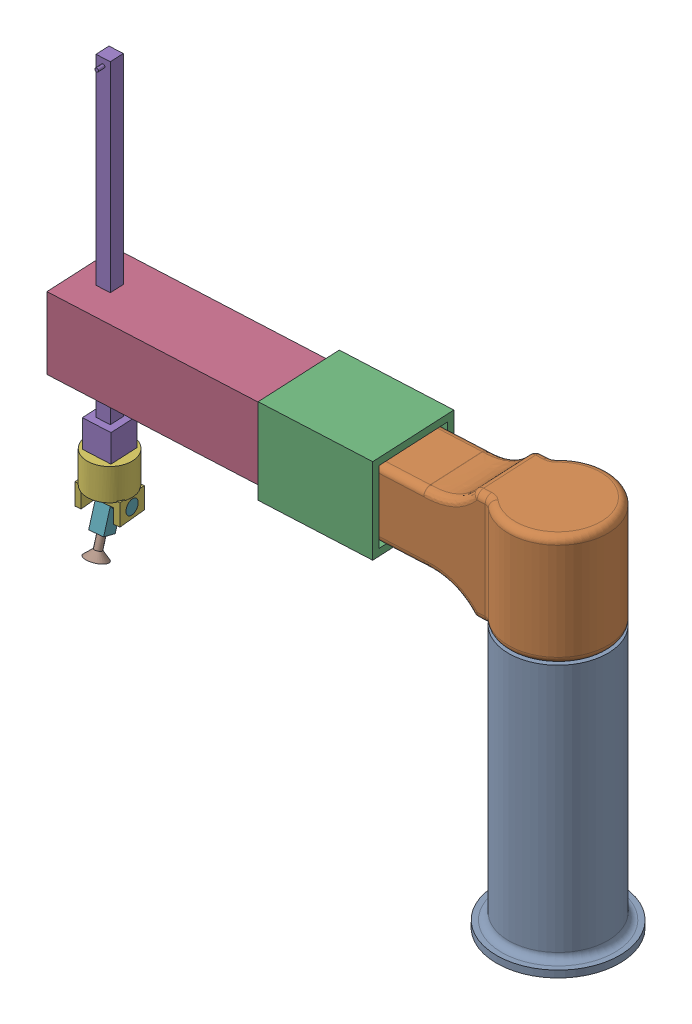
SolidWorks assembly Full_Assem_2023, configuration Default. Lengths in mm.
Overall size (758.51 810.22 185.22).
7 component instances, 7 part files, 12 mates.
Components (placement in the parent):
- JayRPPBase-1: JayRPPBase [Default] at (685.9932 606.079 1289.2915) size (180 424 180)
- JayRPPRotation-1: JayRPPRotation [Default] at (685.9932 990.079 1289.2915) x (-0.998787 0 0.04923) z (-0.04923 0 -0.998787) size (464.5 166.03 145)
- JayRPPPrismatic1-2: JayRPPPrismatic1 [Default] at (324.1942 1071.079 1307.1244) x (-0.998787 0 0.04923) z (0.04923 0 0.998787) size (464 125 125)
- JayRPPPrismatic2-1: JayRPPPrismatic2 [Default] at (60.5143 916.3025 1320.1209) x (0.998787 0 -0.04923) z (0.04923 0 0.998787) size (40 540 40)
- jaywrist1-1: jaywrist1 [Default] at (60.5143 870.3025 1320.1209) x (-0.101882 0 -0.994796) z (0.994796 0 -0.101882) size (65 75.53 65)
- jaywrist2-1: jaywrist2 [Default] at (60.5143 855.5395 1320.1209) x (0.096679 0.315479 0.943995) z (0.994796 0 -0.101882) size (20 50 60)
- Jaytool-1: Jaytool [Default] at (62.7643 789.1142 1342.0895) x (0.99837 0.015664 -0.054886) z (0.047167 0.315089 0.947889) size (30 40 30)
Mates (geometry in assembly coordinates):
- Coincident2: coincident anti-aligned: plane of JayRPPBase-1 through (685.9932 1030.079 1289.2915) normal (0 1 0); plane of JayRPPRotation-1 through (685.9932 1030.079 1289.2915) normal (0 -1 0)
- Concentric1: concentric aligned: cylinder of JayRPPBase-1 through (685.9932 1030.079 1289.2915) axis (0 -1 0) radius 10; cylinder of JayRPPRotation-1 through (685.9932 1030.079 1289.2915) axis (0 -1 0) radius 10
- Coincident3: coincident anti-aligned: plane of JayRPPRotation-1 through (446.7765 1081.079 1311.0945) normal (-0.04923 0 -0.998787); plane of JayRPPPrismatic1-2 through (476.5022 1061.079 1309.6293) normal (0.04923 0 0.998787)
- Coincident4: coincident anti-aligned: plane of JayRPPRotation-1 through (445.7919 1081.079 1291.1187) normal (0 -1 0); plane of JayRPPPrismatic1-2 through (475.5176 1081.079 1289.6536) normal (0 1 0)
- Coincident5: coincident anti-aligned: plane of JayRPPPrismatic1-2 through (51.0188 963.579 1330.6011) normal (0.998787 0 -0.04923); plane of JayRPPPrismatic2-1 through (50.0342 1416.3025 1310.6254) normal (-0.998787 0 0.04923)
- Coincident6: coincident anti-aligned: plane of JayRPPPrismatic1-2 through (70.0099 963.579 1309.6408) normal (0.04923 0 0.998787); plane of JayRPPPrismatic2-1 through (50.0342 1416.3025 1310.6254) normal (-0.04923 0 -0.998787)
- Coincident7: coincident anti-aligned: plane of JayRPPPrismatic2-1 through (60.5143 876.3025 1320.1209) normal (0 -1 0); plane of jaywrist1-1 through (60.5143 876.3025 1320.1209) normal (0 1 0)
- Concentric2: concentric aligned: cylinder of JayRPPPrismatic2-1 through (60.5143 876.3025 1320.1209) axis (0 1 0) radius 10; cylinder of jaywrist1-1 through (60.5143 876.3025 1320.1209) axis (0 1 0) radius 10
- Coincident8: coincident anti-aligned: circle of jaywrist1-1; plane of jaywrist2-1 through (30.6704 855.5395 1323.1774) normal (-0.994796 0 0.101882)
- Concentric3: concentric anti-aligned: cylinder of jaywrist1-1 through (18.7329 855.5395 1324.4) axis (0.994796 0 -0.101882) radius 10; cylinder of jaywrist2-1 through (90.3582 855.5395 1317.0645) axis (-0.994796 0 0.101882) radius 10
- Coincident9: coincident anti-aligned: plane of jaywrist2-1 through (61.4786 827.0716 1329.5361) normal (0.032142 -0.948933 0.313837); plane of Jaytool-1 through (61.4786 827.0716 1329.5361) normal (-0.032142 0.948933 -0.313837)
- Concentric4: concentric anti-aligned: cylinder of jaywrist2-1 through (61.4786 827.0716 1329.5361) axis (0.032142 -0.948933 0.313837) radius 5; cylinder of Jaytool-1 through (61.4786 827.0716 1329.5361) axis (-0.032142 0.948933 -0.313837) radius 5
